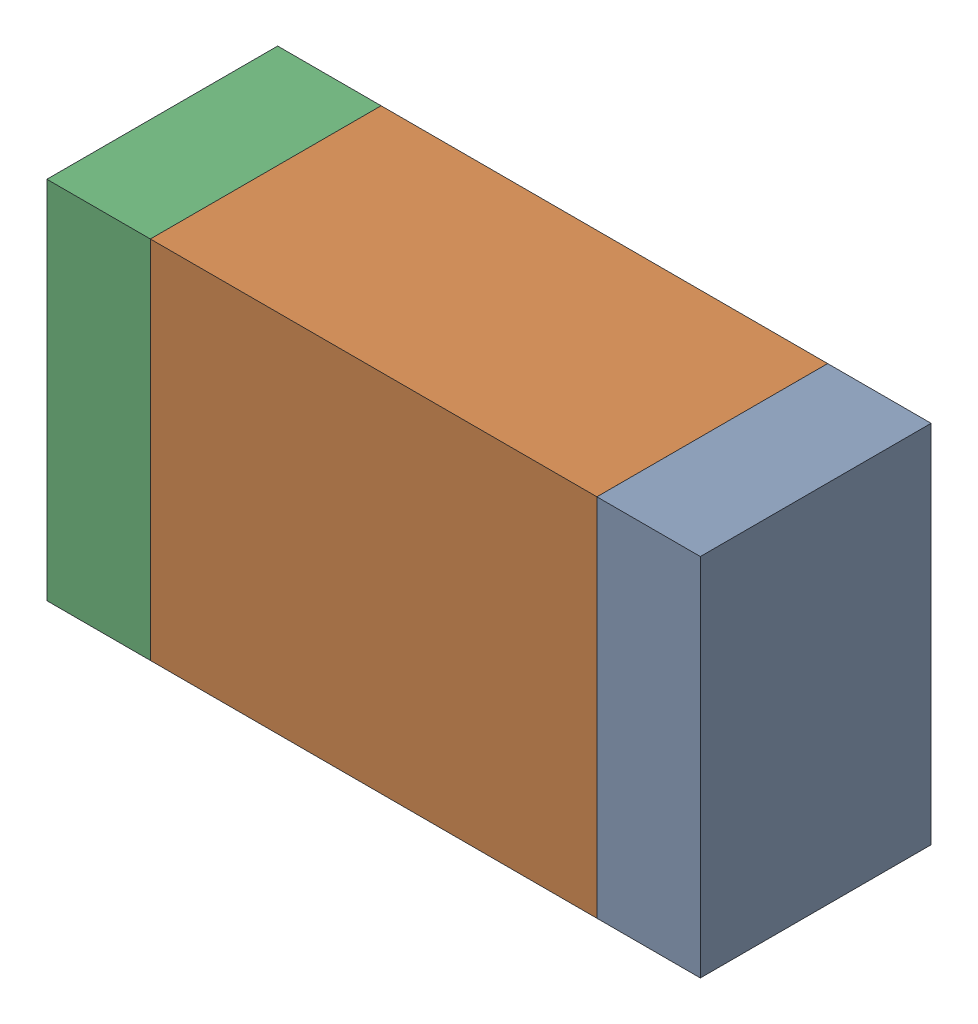
SolidWorks assembly R4-2, configuration Default. Lengths in mm.
Overall size (1.7 0.95 0.6).
6 component instances, 2 part files, 0 mates.
Components (placement in the parent):
- 959209072-2-1: 959209072-2 [Default] at (119.5871 82.2961 0) size (0.27 0.95 0.6)
  - Extruded-83-1: Extruded-83 [Default] at origin size (0.27 0.95 0.6)
- 959209208-2-1: 959209208-2 [Default] at (118.8721 82.2961 0) size (1.16 0.95 0.6)
  - Extruded-84-1: Extruded-84 [Default] at origin size (1.16 0.95 0.6)
- 959209072-2-2: 959209072-2 [Default] at (118.1571 82.2961 0) size (0.27 0.95 0.6)
  - Extruded-83-1: Extruded-83 [Default] at origin size (0.27 0.95 0.6)
